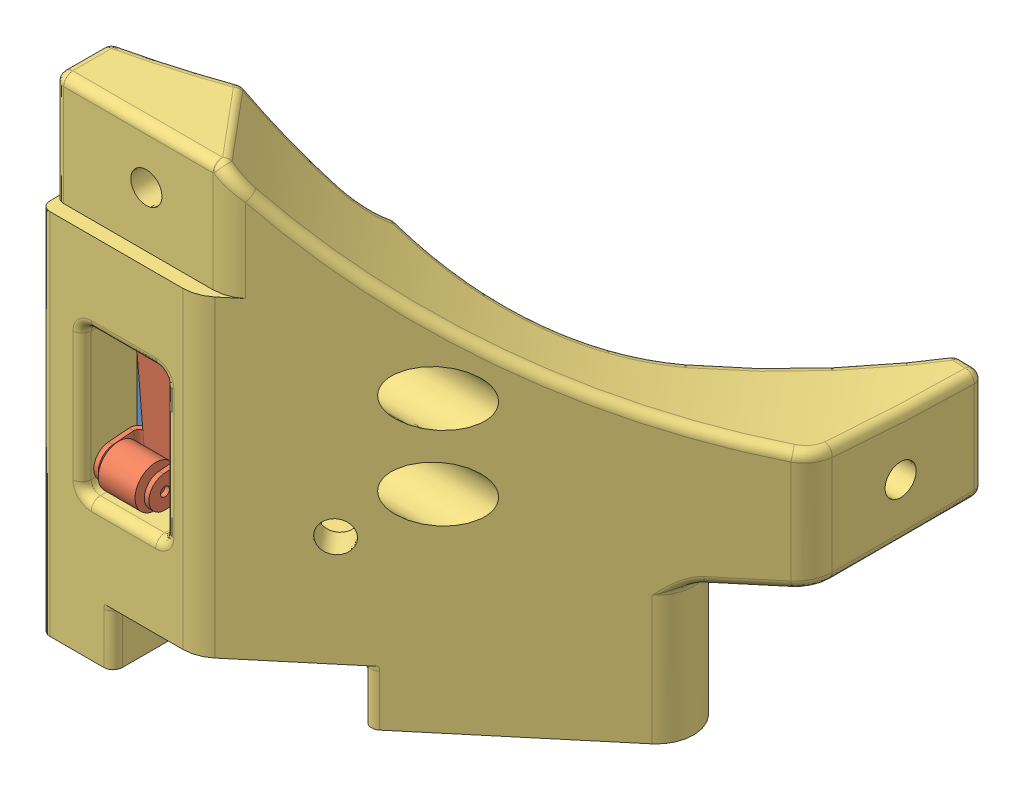
SolidWorks assembly Angle, configuration Défaut. Lengths in mm.
Overall size (53.5 52 51.1).
4 component instances, 3 part files, 3 mates.
Components (placement in the parent):
- microswitchGaletAss-1: microswitchGaletAss [Défaut] at (90 44 75) x (0 -1 0) z (-1 0 0) size (21.06 21.1 7)
  - microswitchGalet02-1: microswitchGalet02 [Défaut] at origin size (20 15 7)
  - microswitchGalet01-1: microswitchGalet01 [Défaut] at (1.7099 12.1145 0) x (0.996636 -0.081957 0) z (0 0 1) size (19 9 6)
- Angle_support-1: Angle_support [Défaut] at (91 7 50) size (53.5 52 49)
Mates (geometry in assembly coordinates):
- Coïncidente439: coincident: plane of assembly; plane of assembly; plane of microswitchGaletAss-1/microswitchGalet02-1 through (93.5 44 75) normal (1 0 0); plane of Angle_support-1 through (93.5 7 50) normal (-1 0 0)
- Coaxiale164: concentric: cylinder of assembly; cylinder of assembly; cylinder of microswitchGaletAss-1/microswitchGalet02-1 through (86.5 38.5 78) axis (1 0 0) radius 1; cylinder of Angle_support-1 through (134.5 38.5 78) axis (-1 0 0) radius 1.5
- Coaxiale165: concentric: cylinder of assembly; cylinder of assembly; cylinder of microswitchGaletAss-1/microswitchGalet02-1 through (86.5 29.5 78) axis (1 0 0) radius 1; cylinder of Angle_support-1 through (134.5 29.5 78) axis (-1 0 0) radius 1.5
